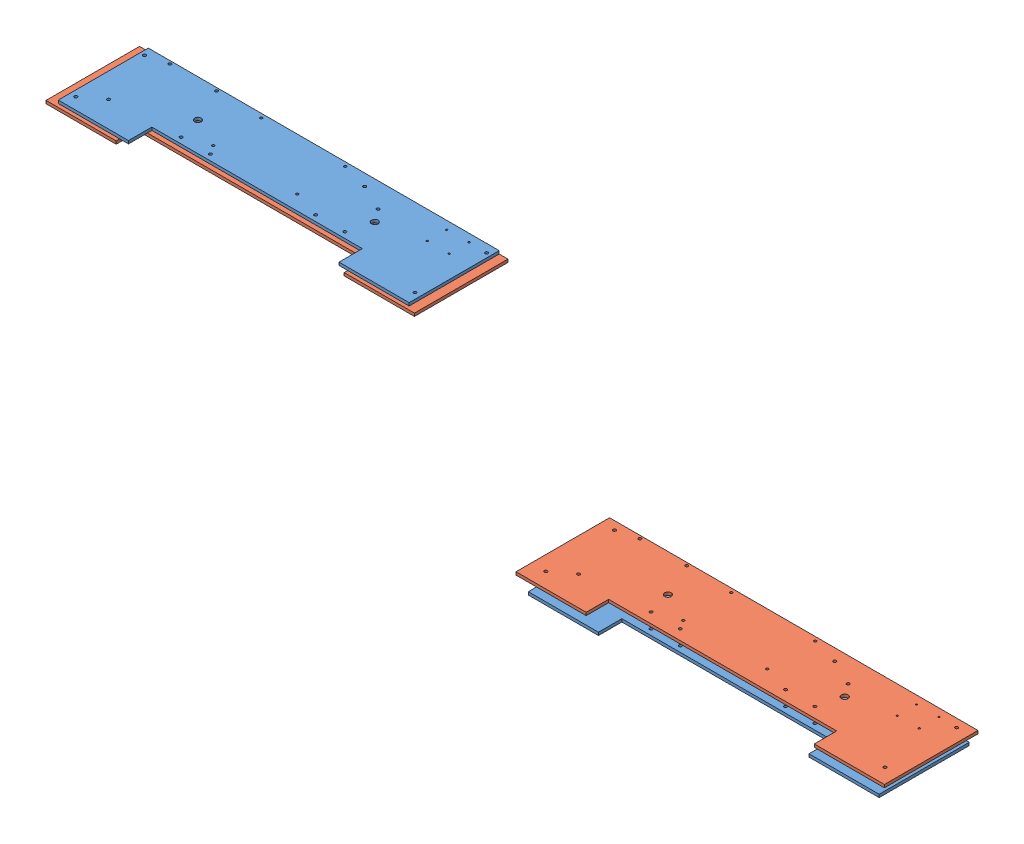
SolidWorks assembly Flat Boards Reference Assemblys, configuration Default. Lengths in mm.
Overall size (1901.11 340.29 283.52).
4 component instances, 2 part files, 6 mates.
Components (placement in the parent):
- Flat Board V2-1: Flat Board V2 [Default] at (-275.9583 26.6772 51.6992) size (762 6.35 195.58)
- Flat Board V3-1: Flat Board V3 [Default] at (-295.0083 58.4272 61.3004) size (800.1 6.35 203.2)
- Flat Board V2-2: Flat Board V2 [Default] at (-1376.9724 360.6159 -28.6203) size (762 6.35 195.58)
- Flat Board V3-2: Flat Board V3 [Default] at (-1396.0224 354.2659 -19.0191) size (800.1 6.35 203.2)
Mates (geometry in assembly coordinates):
- Distance11: distance = 38.1 mm anti-aligned: plane of Flat Board V3-1 through (-295.0083 64.7772 61.3004) normal (0 1 0); plane of Flat Board V2-1 through (-275.9583 26.6772 51.6992) normal (0 -1 0)
- Coincident27: coincident aligned: plane of Flat Board V2-1 through (333.6417 33.0272 -93.0808) normal (0 0 -1); plane of Flat Board V3-1 through (352.6917 64.7772 -93.0808) normal (0 0 -1)
- Distance15: distance = 19.05 mm aligned: plane of Flat Board V2-1 through (333.6417 33.0272 102.4992) normal (1 0 0); plane of Flat Board V3-1 through (352.6917 64.7772 110.1192) normal (1 0 0)
- Concentric1: concentric aligned: circle of Flat Board V2-2; circle of Flat Board V3-2
- Concentric2: concentric aligned: circle of Flat Board V2-2; circle of Flat Board V3-2
- Coincident31: coincident aligned: circle of Flat Board V2-2; circle of Flat Board V3-2
